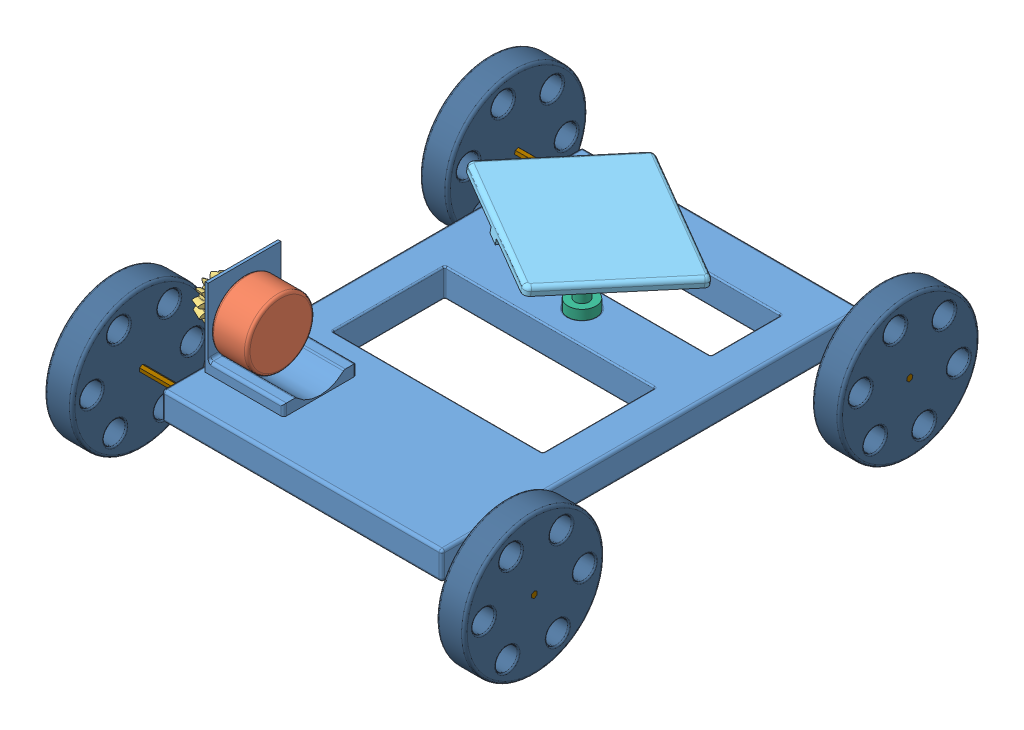
SolidWorks assembly Wang-PrelimDesign, configuration Default. Lengths in mm.
Overall size (150 71.11 197.83).
22 component instances, 10 part files, 47 mates.
Components (placement in the parent):
- Chassis-1: Chassis [Default] at origin size (100 38 150)
- Wang-MotorPinion-2: Wang-MotorPinion [Default] at (10 22.354 -26) x (0 0.866025 0.5) z (-1 0 0) size (24 24 25.75)
  - Motor-1: Motor [Default] at origin size (24 24 25)
  - straight bevel pinion_ai-1: straight bevel pinion_ai [Inch - Straight bevel pinion 24DP12PT 35GT 14.5PA 0.15FW ---12O0.175H0.875MD0.0938N] at (0 0 14.8266) x (0 0 1) z (-0.141382 -0.989955 0) size (7.78 14.9 14.9)
- M2X6-Screw-1: M2X6-Screw [Default] at (22.858 31.344 -27.5836) size (7.4 4 4)
  - pan head tapping screw_am-1: pan head tapping screw_am [PHT 2x6x5.2-slot-D-S] at (-21.758 -1.6288 5.8336) size (7.45 4 4)
- M2X6-Screw-2: M2X6-Screw [Default] at (23.0227 31.344 -36.0836) size (7.4 4 4)
  - pan head tapping screw_am-1: pan head tapping screw_am [PHT 2x6x5.2-slot-D-S] at (-21.758 -1.6288 5.8336) size (7.45 4 4)
- Wang-SolarPowerSystem-New-1: Wang-SolarPowerSystem-New [Default] at (50 33 -100) x (-0.593255 0 -0.805015) z (-0.805015 0 0.593255) size (70.79 37.37 68.68)
  - Solar Panel-1: Solar Panel [Default] at (10.4392 1.468 -24.0892) x (-0.410009 -0.134343 0.902133) z (0.91192 -0.041749 0.40824) size (50 8 55)
  - BallCasterJoyStick-Socket-2: BallCasterJoyStick-Socket [Default] at origin size (12.6 21.53 11.89)
  - BallCasterJoyStick-Ball-2: BallCasterJoyStick-Ball [Default] at (0.1546 0.0895 -1.2566) x (-0.05017 -0.140325 0.988834) z (-0.998593 -0.009984 -0.052082) size (10 16 10)
- Axle-2.3mm-Boss-Washer-1: Axle-2.3mm-Boss-Washer [Default] at (-60 5 -8) x (1 0 0) z (0 0.535701 0.844408) size (15 4 4)
- Axle-2.3mm-Boss-Washer-2: Axle-2.3mm-Boss-Washer [Default] at (-60 5 -142) x (1 0 0) z (0 -0.686372 -0.72725) size (15 4 4)
- Axle-2.3mm-Boss-Washer-3: Axle-2.3mm-Boss-Washer [Default] at (25 5 -8) x (1 0 0) z (0 -0.999129 0.041727) size (15 4 4)
- Axle-2.3mm-Boss-Washer-4: Axle-2.3mm-Boss-Washer [Default] at (25 5 -142) x (1 0 0) z (0 -0.973003 0.230791) size (15 4 4)
- Axle-2.3mm-Axle-Hex-2mm-1: Axle-2.3mm-Axle-Hex-2mm [Default] at (50 5 -142) x (1 0 0) z (0 -0.686372 -0.72725) size (150 2 2.31)
- Axle-2.3mm-Axle-Hex-2mm-2: Axle-2.3mm-Axle-Hex-2mm [Default] at (50 5 -8) x (1 0 0) z (0 0.999129 -0.041727) size (150 2 2.31)
- Wheel-17: Wheel [Default] at (-25 5 -8) x (0 0.999129 -0.041727) z (1 0 0) size (50 50 10)
- Wheel-18: Wheel [Default] at (-25 5 -142) x (0 -0.973003 0.230791) z (1 0 0) size (50 50 10)
- Wheel-19: Wheel [Default] at (115 5 -142) x (0 -0.973003 0.230791) z (1 0 0) size (50 50 10)
- Wheel-20: Wheel [Default] at (115 5 -8) x (0 -0.463428 0.886135) z (1 0 0) size (50 50 10)
Mates (geometry in assembly coordinates):
- Concentric5: concentric aligned: circle of Chassis-1; circle of Wang-MotorPinion-2/Motor-1
- Coincident2: coincident anti-aligned: plane of Chassis-1 through (3.5 38 -13) normal (1 0 0); plane of Wang-MotorPinion-2/Motor-1 through (3.5 22.354 -26) normal (-1 0 0)
- Concentric6: concentric aligned: circle of Chassis-1; circle of Wang-MotorPinion-2/Motor-1
- Concentric7: concentric aligned: circle of Chassis-1; circle of M2X6-Screw-1/pan head tapping screw_am-1
- Coincident3: coincident anti-aligned: plane of Chassis-1 through (2.5 14 -39) normal (-1 0 0); plane of M2X6-Screw-1/pan head tapping screw_am-1 through (2.5 31.7152 -21.75) normal (1 0 0)
- Concentric8: concentric aligned: circle of Chassis-1; circle of M2X6-Screw-2/pan head tapping screw_am-1
- Concentric9: concentric aligned: circle of Chassis-1; circle of Wang-SolarPowerSystem-New-1/BallCasterJoyStick-Socket-2
- Coincident5: coincident anti-aligned: plane of Chassis-1 through (50 5 -100) normal (0 1 0); plane of Wang-SolarPowerSystem-New-1/BallCasterJoyStick-Socket-2 through (50 5 -100) normal (0 -1 0)
- Concentric10: concentric anti-aligned: circle of Chassis-1; circle of Axle-2.3mm-Boss-Washer-2
- Concentric11: concentric anti-aligned: circle of Chassis-1; circle of Axle-2.3mm-Boss-Washer-1
- Concentric12: concentric anti-aligned: circle of Chassis-1; circle of Axle-2.3mm-Boss-Washer-4
- Concentric13: concentric anti-aligned: circle of Chassis-1; circle of Axle-2.3mm-Boss-Washer-3
- Coincident11: coincident anti-aligned: plane of Axle-2.3mm-Boss-Washer-2 through (0 5.7926 -141.1602) normal (0 -0.230791 -0.973003); plane of Axle-2.3mm-Axle-Hex-2mm-1 through (125 5.7926 -141.1602) normal (0 0.230791 0.973003)
- Coincident12: coincident anti-aligned: plane of Axle-2.3mm-Boss-Washer-2 through (0 4.669 -140.8937) normal (0 0.72725 -0.686372); plane of Axle-2.3mm-Axle-Hex-2mm-1 through (125 4.669 -140.8937) normal (0 -0.72725 0.686372)
- Concentric14: concentric anti-aligned: cylinder of Chassis-1 through (100 5 -142) axis (-1 0 0) radius 2; cylinder of Axle-2.3mm-Boss-Washer-2 through (0 5 -142) axis (1 0 0) radius 2
- Tangent1: tangent aligned: cylinder of Chassis-1 through (100 5 -142) axis (-1 0 0) radius 2; cylinder of Axle-2.3mm-Boss-Washer-2 through (0 5 -142) axis (1 0 0) radius 2
- Concentric15: concentric anti-aligned: cylinder of Chassis-1 through (100 5 -142) axis (-1 0 0) radius 2; cylinder of Axle-2.3mm-Boss-Washer-4 through (85 5 -142) axis (1 0 0) radius 2
- Tangent2: tangent aligned: cylinder of Chassis-1 through (100 5 -142) axis (-1 0 0) radius 2; cylinder of Axle-2.3mm-Boss-Washer-4 through (85 5 -142) axis (1 0 0) radius 2
- Coincident14: coincident anti-aligned: plane of Axle-2.3mm-Boss-Washer-4 through (85 4.669 -140.8937) normal (0 0.72725 -0.686372); plane of Axle-2.3mm-Axle-Hex-2mm-1 through (125 4.669 -140.8937) normal (0 -0.72725 0.686372)
- Coincident15: coincident anti-aligned: plane of Axle-2.3mm-Boss-Washer-4 through (85 4.669 -140.8937) normal (0 0.72725 -0.686372); plane of Axle-2.3mm-Axle-Hex-2mm-1 through (125 4.669 -140.8937) normal (0 -0.72725 0.686372)
- Coincident16: coincident aligned: plane of Chassis-1 through (100 10 -150) normal (1 0 0); plane of Axle-2.3mm-Boss-Washer-4 through (100 5 -142) normal (1 0 0)
- Distance1: distance = 25 mm aligned: plane of Axle-2.3mm-Axle-Hex-2mm-1 through (125 5 -142) normal (1 0 0); plane of Chassis-1 through (100 10 -150) normal (1 0 0)
- Coincident18: coincident anti-aligned: plane of Axle-2.3mm-Boss-Washer-3 through (85 5.5351 -9.0232) normal (0 -0.844408 0.535701); plane of Axle-2.3mm-Axle-Hex-2mm-2 through (125 5.5351 -9.0232) normal (0 0.844408 -0.535701)
- Coincident20: coincident anti-aligned: plane of Axle-2.3mm-Boss-Washer-3 through (85 3.8463 -7.9518) normal (0 0.886135 0.463428); plane of Axle-2.3mm-Axle-Hex-2mm-2 through (125 3.8463 -7.9518) normal (0 -0.886135 -0.463428)
- Concentric16: concentric anti-aligned: cylinder of Chassis-1 through (100 5 -8) axis (-1 0 0) radius 2; cylinder of Axle-2.3mm-Boss-Washer-3 through (85 5 -8) axis (1 0 0) radius 2
- Tangent3: tangent aligned: cylinder of Chassis-1 through (100 5 -8) axis (-1 0 0) radius 2; cylinder of Axle-2.3mm-Boss-Washer-3 through (85 5 -8) axis (1 0 0) radius 2
- Coincident21: coincident aligned: plane of Chassis-1 through (100 10 -150) normal (1 0 0); plane of Axle-2.3mm-Boss-Washer-3 through (100 5 -8) normal (1 0 0)
- Concentric17: concentric anti-aligned: cylinder of Chassis-1 through (100 5 -8) axis (-1 0 0) radius 2; cylinder of Axle-2.3mm-Boss-Washer-1 through (0 5 -8) axis (1 0 0) radius 2
- Coincident22: coincident anti-aligned: plane of Chassis-1 through (0 10 0) normal (-1 0 0); circle of Axle-2.3mm-Boss-Washer-1
- Coincident23: coincident anti-aligned: plane of Axle-2.3mm-Boss-Washer-1 through (0 4.3814 -8.975) normal (0 0.041727 0.999129); plane of Axle-2.3mm-Axle-Hex-2mm-2 through (125 4.3814 -8.975) normal (0 -0.041727 -0.999129)
- Coincident24: coincident anti-aligned: plane of Axle-2.3mm-Boss-Washer-1 through (0 4.4649 -6.9768) normal (0 0.844408 -0.535701); plane of Axle-2.3mm-Axle-Hex-2mm-2 through (125 4.4649 -6.9768) normal (0 -0.844408 0.535701)
- Distance2: distance = 25 mm aligned: plane of Axle-2.3mm-Axle-Hex-2mm-2 through (125 5 -8) normal (1 0 0); plane of Chassis-1 through (100 10 -150) normal (1 0 0)
- Coincident35: coincident aligned: plane of Chassis-1 through (0 10 0) normal (-1 0 0); plane of Axle-2.3mm-Boss-Washer-2 through (0 5 -142) normal (-1 0 0)
- Coincident41: coincident anti-aligned: plane of Axle-2.3mm-Axle-Hex-2mm-2 through (125 3.8463 -7.9518) normal (0 -0.886135 -0.463428); plane of Wheel-20 through (111.9449 3.8463 -7.9518) normal (0 0.886135 0.463428)
- Coincident42: coincident anti-aligned: plane of Axle-2.3mm-Axle-Hex-2mm-2 through (125 5.6186 -7.025) normal (0 0.041727 0.999129); plane of Wheel-20 through (111.9449 5.6186 -7.025) normal (0 -0.041727 -0.999129)
- Coincident43: coincident aligned: plane of Axle-2.3mm-Axle-Hex-2mm-2 through (125 5 -8) normal (1 0 0); plane of Wheel-20 through (125 5 -8) normal (1 0 0)
- Coincident44: coincident anti-aligned: plane of Axle-2.3mm-Axle-Hex-2mm-2 through (125 3.8463 -7.9518) normal (0 -0.886135 -0.463428); plane of Wheel-17 through (-28.0551 3.8463 -7.9518) normal (0 0.886135 0.463428)
- Coincident45: coincident anti-aligned: plane of Axle-2.3mm-Axle-Hex-2mm-2 through (125 5.6186 -7.025) normal (0 0.041727 0.999129); plane of Wheel-17 through (-28.0551 5.6186 -7.025) normal (0 -0.041727 -0.999129)
- Coincident46: coincident aligned: plane of Axle-2.3mm-Axle-Hex-2mm-2 through (-25 5 -8) normal (-1 0 0); plane of Wheel-17 through (-25 5 -8) normal (-1 0 0)
- Coincident47: coincident anti-aligned: plane of Axle-2.3mm-Axle-Hex-2mm-1 through (125 5.331 -143.1063) normal (0 0.72725 -0.686372); plane of Wheel-18 through (-28.0551 5.331 -143.1063) normal (0 -0.72725 0.686372)
- Coincident48: coincident anti-aligned: plane of Axle-2.3mm-Axle-Hex-2mm-1 through (125 4.669 -140.8937) normal (0 -0.72725 0.686372); plane of Wheel-18 through (-28.0551 4.669 -140.8937) normal (0 0.72725 -0.686372)
- Coincident49: coincident anti-aligned: plane of Axle-2.3mm-Axle-Hex-2mm-1 through (125 4.2074 -142.8398) normal (0 -0.230791 -0.973003); plane of Wheel-18 through (-28.0551 4.2074 -142.8398) normal (0 0.230791 0.973003)
- Coincident50: coincident aligned: plane of Axle-2.3mm-Axle-Hex-2mm-1 through (-25 5 -142) normal (-1 0 0); plane of Wheel-18 through (-25 5 -142) normal (-1 0 0)
- Coincident51: coincident anti-aligned: plane of Axle-2.3mm-Axle-Hex-2mm-1 through (125 3.8765 -141.7335) normal (0 -0.958041 -0.286631); plane of Wheel-19 through (111.9449 3.8765 -141.7335) normal (0 0.958041 0.286631)
- Coincident52: coincident anti-aligned: plane of Axle-2.3mm-Axle-Hex-2mm-1 through (125 6.1235 -142.2665) normal (0 0.958041 0.286631); plane of Wheel-19 through (111.9449 6.1235 -142.2665) normal (0 -0.958041 -0.286631)
- Coincident53: coincident anti-aligned: plane of Axle-2.3mm-Axle-Hex-2mm-1 through (125 5.7926 -141.1602) normal (0 0.230791 0.973003); plane of Wheel-19 through (111.9449 5.7926 -141.1602) normal (0 -0.230791 -0.973003)
- Coincident54: coincident aligned: plane of Axle-2.3mm-Axle-Hex-2mm-1 through (125 5 -142) normal (1 0 0); plane of Wheel-19 through (125 5 -142) normal (1 0 0)
